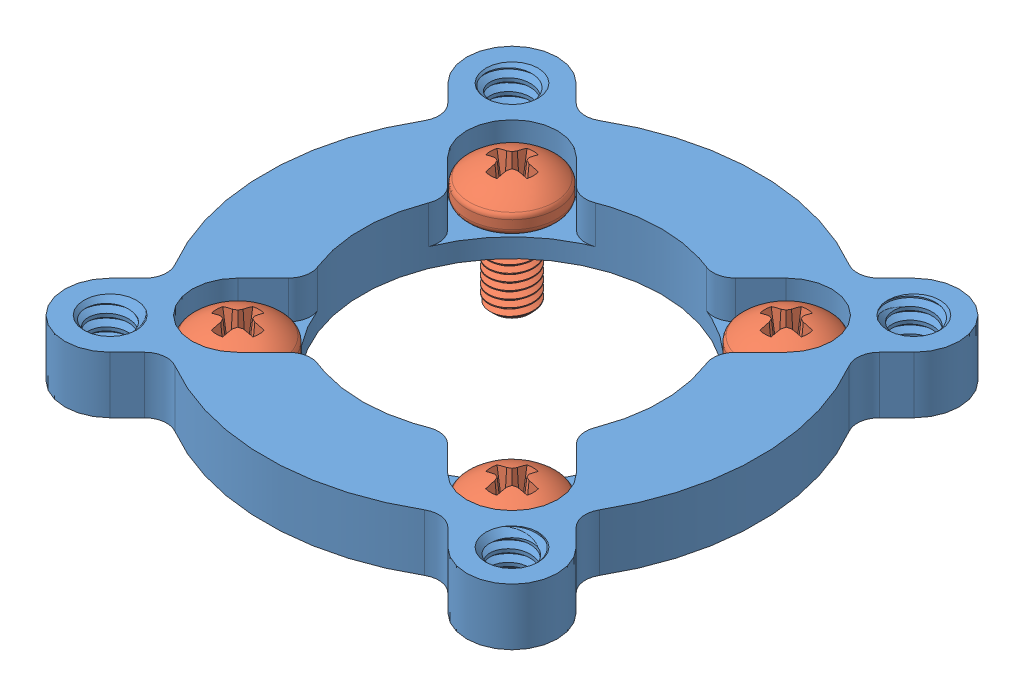
SolidWorks assembly 555174 assembly, configuration Default. Lengths in mm.
Overall size (33.02 8.74 33.02).
5 component instances, 2 part files, 0 mates.
Components (placement in the parent):
- 555174-1: 555174 [Default] at (-58.8675 33.2863 7.1552) size (33.02 4.05 33.02)
- 555174 screw_92005A116-1: 555174 screw_92005A116 [Default] at (-68.0596 28.5563 -2.0369) x (1 0 0) z (0 1 0) size (6 6 8.48)
- 555174 screw_92005A116-2: 555174 screw_92005A116 [Default] at (-68.0596 28.5563 16.3474) x (0 0 -1) z (0 1 0) size (6 6 8.48)
- 555174 screw_92005A116-3: 555174 screw_92005A116 [Default] at (-49.6753 28.5563 16.3474) x (-1 0 0) z (0 1 0) size (6 6 8.48)
- 555174 screw_92005A116-4: 555174 screw_92005A116 [Default] at (-49.6753 28.5563 -2.0369) x (0 0 1) z (0 1 0) size (6 6 8.48)
